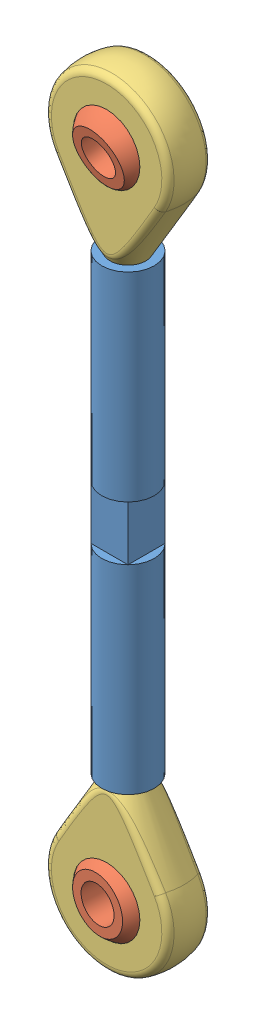
SolidWorks assembly Rod assem, configuration Default. Lengths in mm.
Overall size (18 109.5 11.28).
5 component instances, 3 part files, 11 mates.
Components (placement in the parent):
- platform rods-1: platform rods [Default] at origin size (7.37 63.5 7.37)
- uxcell SA5T ball-1: uxcell SA5T ball [Default] at (0 -14 0) x (-0.470362 0.882255 -0.019631) z (-0.070359 -0.015317 0.997404) size (11.01 11.01 8)
- uxcell SA5T ball joint housing-1: uxcell SA5T ball joint housing [Default] at (0 -14 0) size (18 42.37 10.1)
- uxcell SA5T ball joint housing-2: uxcell SA5T ball joint housing [Default] at (0 77.5 0) x (-1 0 0) z (0 0 1) size (18 42.37 10.1)
- uxcell SA5T ball-2: uxcell SA5T ball [Default] at (0 77.5 0) x (-0.691325 0.712971 0.117224) z (-0.064779 -0.222745 0.972722) size (11.01 11.01 8)
Mates (geometry in assembly coordinates):
- Coincident1: coincident aligned: plane of platform rods-1 through (0 0 0) normal (0 0 1); plane of assembly through (0 0 0) normal (0 0 1)
- Coincident2: coincident aligned: plane of platform rods-1 through (0 0 0) normal (0 1 0); plane of assembly through (0 0 0) normal (0 1 0)
- Coincident3: coincident aligned: plane of platform rods-1 through (0 0 0) normal (1 0 0); plane of assembly through (0 0 0) normal (1 0 0)
- Concentric1: concentric: sphere of uxcell SA5T ball-1; sphere of uxcell SA5T ball joint housing-1
- Coincident7: coincident aligned: plane of platform rods-1 through (0 0 0) normal (0 -1 0); circle of uxcell SA5T ball joint housing-1
- Coincident8: coincident aligned: plane of platform rods-1 through (0 0 0) normal (0 0 1); plane of uxcell SA5T ball joint housing-1 through (0 -14 0) normal (0 0 1)
- Coincident9: coincident aligned: plane of platform rods-1 through (0 0 0) normal (1 0 0); plane of uxcell SA5T ball joint housing-1 through (0 -14 0) normal (1 0 0)
- Concentric2: concentric: sphere of uxcell SA5T ball joint housing-2; sphere of uxcell SA5T ball-2
- Coincident10: coincident aligned: plane of platform rods-1 through (0 0 0) normal (0 0 1); plane of uxcell SA5T ball joint housing-2 through (0 77.5 0) normal (0 0 1)
- Coincident11: coincident anti-aligned: plane of platform rods-1 through (0 0 0) normal (1 0 0); plane of uxcell SA5T ball joint housing-2 through (0 77.5 0) normal (-1 0 0)
- Coincident12: coincident aligned: plane of platform rods-1 through (0 63.5 0) normal (0 1 0); circle of uxcell SA5T ball joint housing-2
